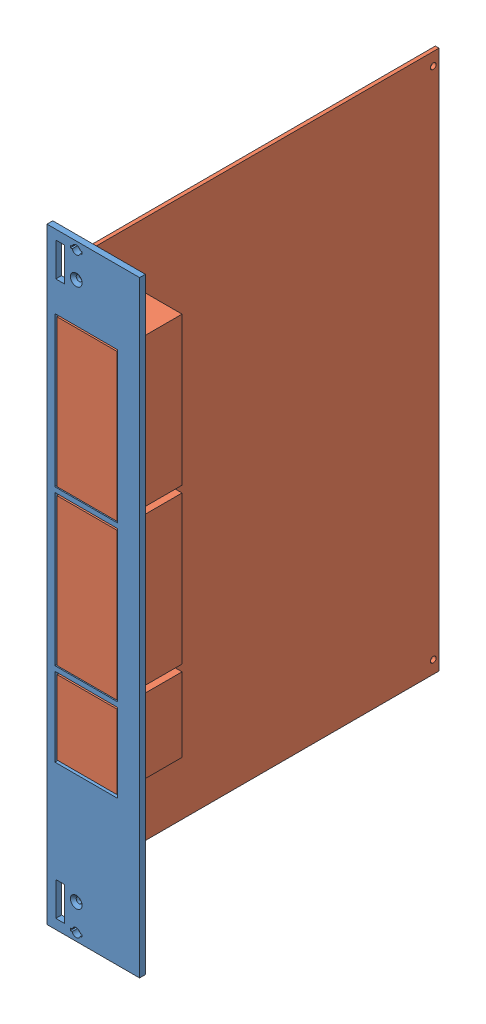
SolidWorks assembly FTSW-bracket, configuration Default. Lengths in mm.
Overall size (40 262 165.5).
3 component instances, 2 part files, 0 mates.
Components (placement in the parent):
- VME-6U-front-panel-2: VME-6U-front-panel [Default] at origin size (40 262 165.5)
  - VME-6U-front-panel-1: VME-6U-front-panel [Default] at origin size (40 262 2.5)
  - VME-6U-PCB.FTSW-1: VME-6U-PCB.FTSW [Default] at (2.25 14 -3) size (27.59 233 165)
